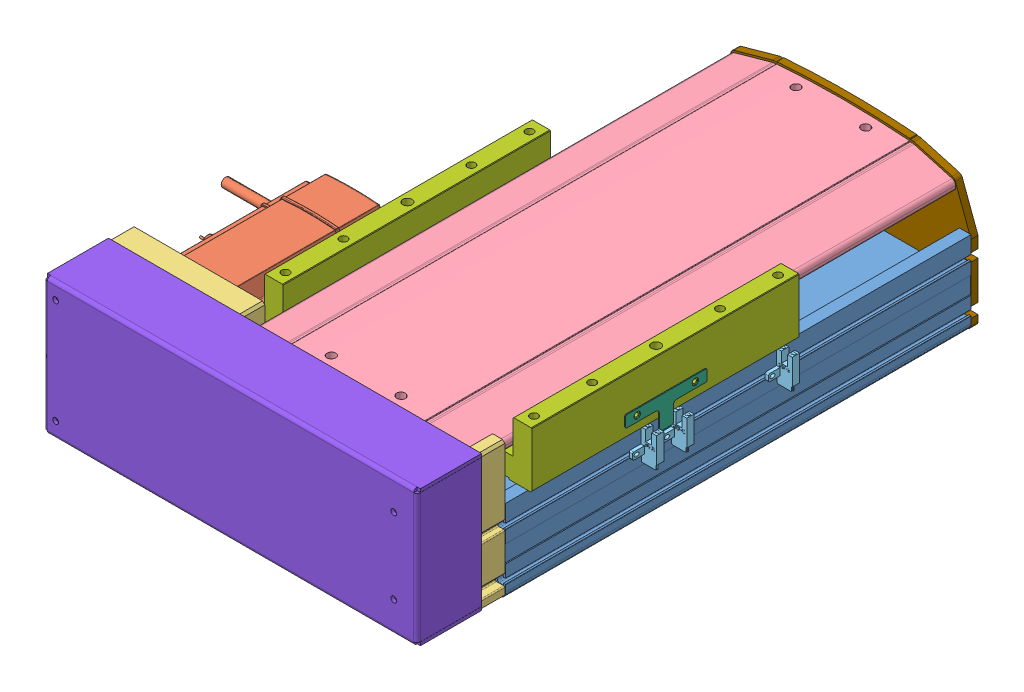
SolidWorks assembly S22-BR-750W, configuration 默认. Lengths in mm.
Overall size (384.91 122 482.01).
11 component instances, 9 part files, 37 mates.
Components (placement in the parent):
- S22-BL底座^S22-BR-750W-1: S22-BL底座^S22-BR-750W [默认] at origin size (220 72.2 400.5) (virtual)
- 750W电机^S22-BR-750W-1: 750W电机^S22-BR-750W [默认] at (-162.71 60.5 58.25) x (0 -1 0) z (0 0 1) size (82 139.7 182) (virtual)
- S22-BR-P75电机板^S22-BR-750W-1: S22-BR-P75电机板^S22-BR-750W [默认] at (-0.21 0.5 200.25) size (321 117 20) (virtual)
- S22-BL上盖^S22-BR-750W-1: S22-BL上盖^S22-BR-750W [默认] at (0 117.9988 10) size (193.4 19.6 420.5) (virtual)
- EE-SX672 传感器^S22-BR-750W-1: EE-SX672 传感器^S22-BR-750W [默认] at (116.75 60.1 83.95) x (1 0 0) z (0 0 -1) size (13.5 27.4 26.1) (virtual)
- S22-GY外置感应片^S22-BR-750W-1: S22-GY外置感应片^S22-BR-750W [默认] at (115.8 87 67.75) x (0 0 1) z (-1 0 0) size (70 27 0.8) (virtual)
- EE-SX672 传感器^S22-BR-750W-2: EE-SX672 传感器^S22-BR-750W [默认] at (116.75 60.1 -32.95) x (1 0 0) z (0 0 -1) size (13.5 27.4 26.1) (virtual)
- EE-SX672 传感器^S22-BR-750W-3: EE-SX672 传感器^S22-BR-750W [默认] at (116.75 60.1 57.85) x (1 0 0) z (0 0 -1) size (13.5 27.4 26.1) (virtual)
- S22-BL-SFS25滑座^S22-BR-750W-1: S22-BL-SFS25滑座^S22-BR-750W [默认] at (0 0 67.75) size (230 80 230) (virtual)
- S22-BL盖子^S22-BR-750W-1: S22-BL盖子^S22-BR-750W [默认] at (-51.21 60.5 275.75) x (-1 0 0) z (0 0 1) size (321.02 117 55.51) (virtual)
- 复件 复件 端盖S22-T22M^S22-BR-750W-1: 复件 复件 端盖S22-T22M^S22-BR-750W [默认] at (0 1.2 -206.25) size (220 118.5 6) (virtual)
Mates (geometry in assembly coordinates):
- 重合1: coincident: plane of S22-BL底座^S22-BR-750W-1 through (0 0 0) normal (1 0 0); plane of assembly through (0 0 0) normal (1 0 0)
- 重合2: coincident: plane of S22-BL底座^S22-BR-750W-1 through (0 0 0) normal (0 1 0); plane of assembly through (0 0 0) normal (0 1 0)
- 重合3: coincident: plane of S22-BL底座^S22-BR-750W-1 through (0 0 0) normal (0 0 1); plane of assembly through (0 0 0) normal (0 0 1)
- 重合28: coincident: plane of S22-BL底座^S22-BR-750W-1 through (0 0 0) normal (0 1 0); plane of S22-BR-P75电机板^S22-BR-750W-1 through (-0.21 0.5 200.25) normal (0 1 0)
- 重合29: coincident: plane of S22-BL底座^S22-BR-750W-1 through (0 0 0) normal (1 0 0); plane of S22-BR-P75电机板^S22-BR-750W-1 through (-0.21 0 200.25) normal (1 0 0)
- 重合30: coincident: plane of S22-BL底座^S22-BR-750W-1 through (-104.5 14 200.25) normal (0 0 1); plane of S22-BR-P75电机板^S22-BR-750W-1 through (-0.21 0.5 200.25) normal (0 0 -1)
- 重合36: coincident: plane of S22-BL底座^S22-BR-750W-1 through (0 0 0) normal (1 0 0); plane of S22-BL上盖^S22-BR-750W-1 through (0 117.9988 10) normal (1 0 0)
- 平行6: parallel: plane of S22-BL底座^S22-BR-750W-1 through (110 16.25 200.25) normal (1 0 0); plane of 750W电机^S22-BR-750W-1 through (-202.71 20.5 58.25) normal (-1 0 0)
- 重合132: coincident: plane of S22-BR-P75电机板^S22-BR-750W-1 through (-0.21 0.5 220.25) normal (0 0 1); plane of S22-BL盖子^S22-BR-750W-1 through (-208.91 2 220.25) normal (0 0 -1)
- 同心52: concentric: cylinder of S22-BL盖子^S22-BR-750W-1 through (-201.71 15.5 265.75) axis (0 0 1) radius 2.5; cylinder of S22-BR-P75电机板^S22-BR-750W-1 through (-201.71 15.5 220.25) axis (0 0 1) radius 1.65
- 同心53: concentric: cylinder of S22-BR-P75电机板^S22-BR-750W-1 through (-201.71 105.5 220.25) axis (0 0 1) radius 1.65; cylinder of S22-BL盖子^S22-BR-750W-1 through (-201.71 105.5 265.75) axis (0 0 1) radius 2.5
- 重合181: coincident: plane of S22-GY外置感应片^S22-BR-750W-1 through (115 91 33.75) normal (-1 0 0); plane of S22-BL-SFS25滑座^S22-BR-750W-1 through (115 122 182.75) normal (1 0 0)
- 同心54: concentric: cylinder of S22-GY外置感应片^S22-BR-750W-1 through (115 87 42.75) axis (1 0 0) radius 2.75; cylinder of S22-BL-SFS25滑座^S22-BR-750W-1 through (115 87 42.75) axis (1 0 0) radius 1.65
- 同心55: concentric: cylinder of S22-GY外置感应片^S22-BR-750W-1 through (115 87 92.75) axis (1 0 0) radius 2.75; cylinder of S22-BL-SFS25滑座^S22-BR-750W-1 through (115 87 92.75) axis (1 0 0) radius 1.65
- 重合182: coincident: plane of EE-SX672 传感器^S22-BR-750W-1 through (110 71.2 77.65) normal (-1 0 0); plane of EE-SX672 传感器^S22-BR-750W-2 through (110 71.2 -39.25) normal (-1 0 0)
- 重合183: coincident: plane of EE-SX672 传感器^S22-BR-750W-1 through (110 71.2 77.65) normal (-1 0 0); plane of EE-SX672 传感器^S22-BR-750W-3 through (110 71.2 51.55) normal (-1 0 0)
- 重合184: coincident: plane of EE-SX672 传感器^S22-BR-750W-1 through (110 49 77.65) normal (0 -1 0); plane of EE-SX672 传感器^S22-BR-750W-3 through (110 49 51.55) normal (0 -1 0)
- 重合185: coincident: plane of EE-SX672 传感器^S22-BR-750W-1 through (110 49 77.65) normal (0 -1 0); plane of EE-SX672 传感器^S22-BR-750W-2 through (110 49 -39.25) normal (0 -1 0)
- 重合186: coincident: plane of EE-SX672 传感器^S22-BR-750W-1 through (113 52.2 67.75) normal (0 0 -1); plane of EE-SX672 传感器^S22-BR-750W-3 through (113 52.2 67.75) normal (0 0 1)
- 重合187: coincident: plane of S22-BL底座^S22-BR-750W-1 through (110 42 200.25) normal (1 0 0); plane of EE-SX672 传感器^S22-BR-750W-1 through (110 71.2 77.65) normal (-1 0 0)
- 距离49: distance = 49 mm: plane of EE-SX672 传感器^S22-BR-750W-3 through (110 49 51.55) normal (0 -1 0); plane of S22-BL底座^S22-BR-750W-1 through (110 0 200.25) normal (0 -1 0)
- Distance1: distance = 122 mm: plane of S22-BL-SFS25滑座^S22-BR-750W-1 through (99 122 182.75) normal (0 1 0); plane of S22-BL底座^S22-BR-750W-1 through (110 0 200.25) normal (0 -1 0)
- Coincident3: coincident: plane of S22-BL底座^S22-BR-750W-1 through (0 0 0) normal (1 0 0); plane of S22-BL-SFS25滑座^S22-BR-750W-1 through (0 0 67.75) normal (1 0 0)
- Distance3: distance = 117.9988 mm: plane of S22-BL上盖^S22-BR-750W-1 through (0 117.9988 10) normal (0 1 0); plane of S22-BL底座^S22-BR-750W-1 through (0 0 0) normal (0 1 0)
- Distance4: distance = 9 mm: plane of 750W电机^S22-BR-750W-1 through (-202.71 27.5 192.25) normal (-1 0 0); plane of S22-BR-P75电机板^S22-BR-750W-1 through (-211.71 118.5 220.25) normal (-1 0 0)
- Distance5: distance = 18 mm: plane of 750W电机^S22-BR-750W-1 through (-195.71 100.5 192.25) normal (0 1 0); plane of S22-BR-P75电机板^S22-BR-750W-1 through (109.29 118.5 220.25) normal (0 1 0)
- Coincident6: coincident: plane of 750W电机^S22-BR-750W-1 through (-162.71 60.5 200.25) normal (0 0 1); plane of S22-BR-P75电机板^S22-BR-750W-1 through (-0.21 0.5 200.25) normal (0 0 -1)
- 距离51: distance = 189 mm: plane of EE-SX672 传感器^S22-BR-750W-1 through (123.5 49 83.95) normal (0 0 1); plane of S22-BL盖子^S22-BR-750W-1 through (-208.91 2 275.75) normal (0 0 1)
- 宽度1: width: plane of EE-SX672 传感器^S22-BR-750W-1 through (123.5 49 77.65) normal (0 0 -1); plane of EE-SX672 传感器^S22-BR-750W-3 through (123.5 49 57.85) normal (0 0 1); plane of S22-GY外置感应片^S22-BR-750W-1 through (115 65 73.75) normal (0 0 1); plane of S22-GY外置感应片^S22-BR-750W-1 through (115 65 61.75) normal (0 0 -1)
- 距离53: distance = 1.2 mm: plane of 复件 复件 端盖S22-T22M^S22-BR-750W-1 through (-110 1.2 -200.25) normal (0 -1 0); plane of S22-BL底座^S22-BR-750W-1 through (110 0 200.25) normal (0 -1 0)
- 宽度2: width: plane of 复件 复件 端盖S22-T22M^S22-BR-750W-1 through (110 18.7 -200.25) normal (1 0 0); plane of 复件 复件 端盖S22-T22M^S22-BR-750W-1 through (-110 18.7 -200.25) normal (-1 0 0); plane of S22-BL底座^S22-BR-750W-1 through (-109.5 27.5 200.25) normal (-1 0 0); plane of S22-BL底座^S22-BR-750W-1 through (109.5 27.5 200.25) normal (1 0 0)
- 重合190: coincident: plane of S22-BL底座^S22-BR-750W-1 through (-104.5 14 -200.25) normal (0 0 -1); plane of 复件 复件 端盖S22-T22M^S22-BR-750W-1 through (92.7005 103.8004 -200.25) normal (0 0 1)
- 重合193: coincident: plane of S22-BL上盖^S22-BR-750W-1 through (59.5897 110.29 -200.25) normal (0 0 -1); plane of 复件 复件 端盖S22-T22M^S22-BR-750W-1 through (92.7005 103.8004 -200.25) normal (0 0 1)
- 距离54: distance = 161 mm: plane of EE-SX672 传感器^S22-BR-750W-2 through (123.5 49 -39.25) normal (0 0 -1); plane of S22-BL底座^S22-BR-750W-1 through (-104.5 14 -200.25) normal (0 0 -1)
- 距离55: distance = 52.71 mm: cylinder of 750W电机^S22-BR-750W-1 through (-162.71 60.5 203.25) axis (0 0 1) radius 9.5; plane of S22-BL底座^S22-BR-750W-1 through (-110 0 200.25) normal (-1 0 0)
- 距离56: distance = 60.5 mm: cylinder of 750W电机^S22-BR-750W-1 through (-162.71 60.5 203.25) axis (0 0 1) radius 9.5; plane of S22-BL底座^S22-BR-750W-1 through (-110 0 200.25) normal (0 -1 0)
- 距离57: distance = 208 mm: cylinder of S22-BL-SFS25滑座^S22-BR-750W-1 through (107 122 67.75) axis (0 1 0) radius 4; plane of S22-BL盖子^S22-BR-750W-1 through (-208.91 2 275.75) normal (0 0 1)
